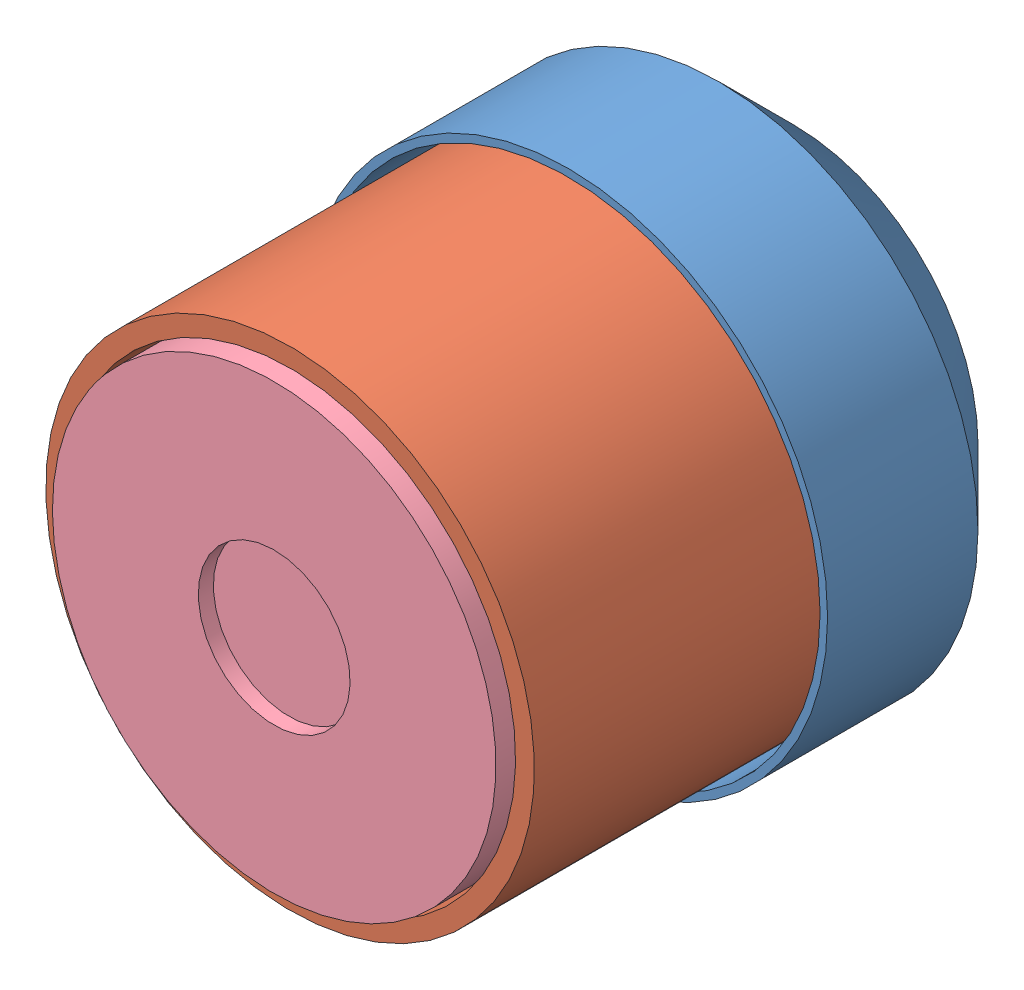
SolidWorks assembly Arm substitute assembly, configuration Default. Lengths in mm.
Overall size (82.61 82.61 73.14).
4 component instances, 4 part files, 4 mates.
Components (placement in the parent):
- Arm substitute 1-1: Arm substitute 1 [Default] at (16.3915 22.8204 16.2487) size (69 69 30)
- Arm substitute 2-2: Arm substitute 2 [Default] at (16.3915 22.8204 83.2487) x (0.10756 -0.994199 0) z (0 0 -1) size (65 65 50)
- partie émant-1: partie émant [Default] at (5.5446 10.721 28.1343) x (0.6675 0.744577 0.00704) z (-0.744455 0.667524 -0.014089) size (32.5 31.14 32.5)
- cover of arm substitute 2-1: cover of arm substitute 2 [Default] at (16.3915 22.8204 85.3638) x (-0.79943 0.60076 0) z (0 0 -1) size (59 59 5)
Mates (geometry in assembly coordinates):
- Concentric1: concentric aligned: cylinder of Arm substitute 1-1 through (16.3915 22.8204 28.2487) axis (0 0 1) radius 33.5; cylinder of Arm substitute 2-2 through (16.3915 22.8204 23.2487) axis (0 0 1) radius 32.5
- Concentric2: concentric: sphere of Arm substitute 1-1; sphere of partie émant-1
- Concentric3: concentric: sphere of Arm substitute 2-2; sphere of partie émant-1
- Concentric4: concentric aligned: cylinder of Arm substitute 2-2 through (16.3915 22.8204 44.2487) axis (0 0 1) radius 30; cylinder of cover of arm substitute 2-1 through (16.3915 22.8204 25.3638) axis (0 0 1) radius 29.5
